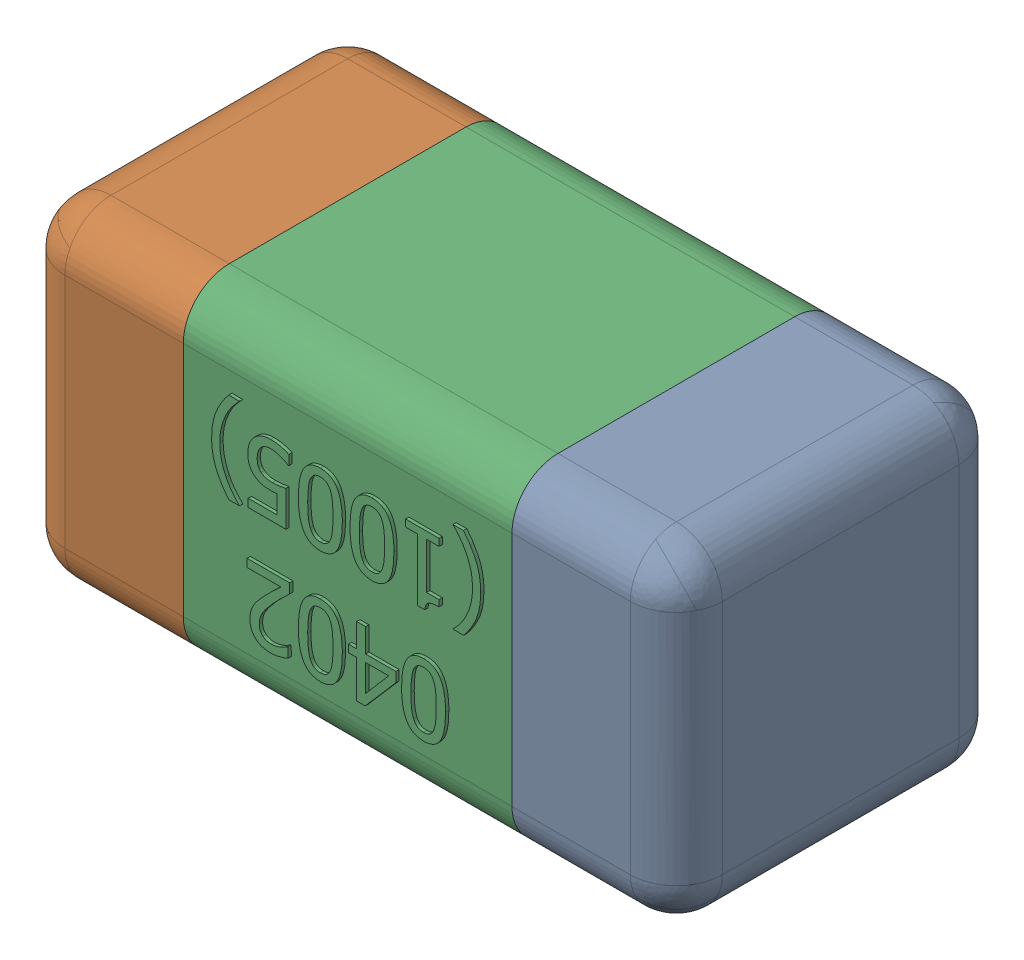
SolidWorks assembly C38, configuration Standard. Lengths in mm.
Overall size (1.01 0.51 0.51).
4 component instances, 3 part files, 0 mates.
Components (placement in the parent):
- C38-subassembly-1-1: C38-subassembly-1 [Standard] at (-9.3001 11.3 0) x (-1 0 0) z (0 0 1) size (1.01 0.51 0.51)
  - User Library-0402_Cap-1: User Library-0402_Cap [Standard] at origin size (0.26 0.51 0.51)
  - User Library-0402_Cap-1-1: User Library-0402_Cap-1 [Standard] at origin size (0.26 0.5 0.51)
  - User Library-0402_Cap-2-1: User Library-0402_Cap-2 [Standard] at origin size (0.5 0.5 0.51)
